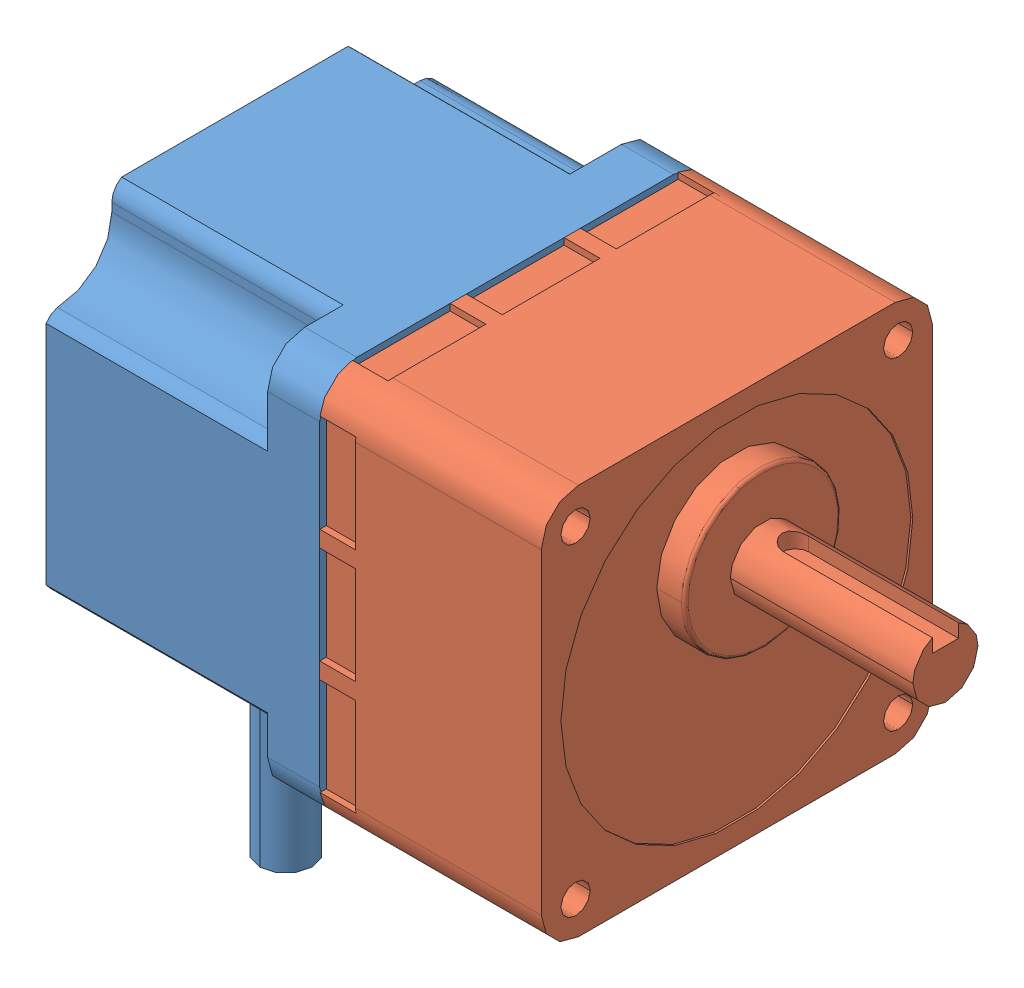
SolidWorks assembly BLHM230K_20_0, configuration Default. Lengths in mm.
Overall size (108 95.5 60).
2 component instances, 2 part files, 3 mates.
Components (placement in the parent):
- BLHM230K_20_0_3-1: BLHM230K_20_0_3 [Default] at (61.6925 -66.4765 -89.8142) size (42 95.5 60)
- BLHM230K_20_0_5-1: BLHM230K_20_0_5 [Default] at (95.6925 -66.4765 -89.8142) size (66 60 60)
Mates (geometry in assembly coordinates):
- 重合/共線/共點1: coincident aligned: circle of BLHM230K_20_0_3-1; cylinder of BLHM230K_20_0_5-1 through (61.6925 -91.2253 -65.0655) axis (-1 0 0) radius 2.25
- 重合/共線/共點2: coincident anti-aligned: plane of BLHM230K_20_0_3-1 through (61.6925 -90.7765 -65.5142) normal (1 0 0); plane of BLHM230K_20_0_5-1 through (61.6925 -90.7765 -65.5142) normal (-1 0 0)
- 同軸心1: concentric aligned: cylinder of BLHM230K_20_0_3-1 through (53.6925 -91.2253 -114.563) axis (-1 0 0) radius 2.25; cylinder of BLHM230K_20_0_5-1 through (61.6925 -91.2253 -114.563) axis (-1 0 0) radius 2.25
